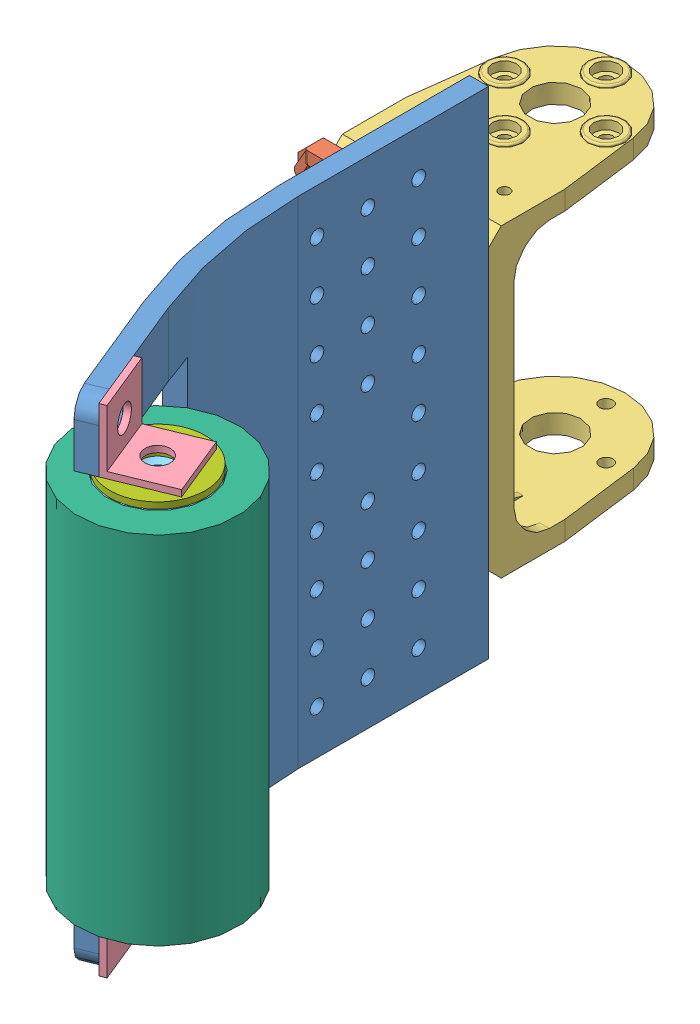
SolidWorks assembly essai_assemblage_pince_3_droite, configuration Default. Lengths in mm.
Overall size (56.85 78 117.91).
10 component instances, 7 part files, 23 mates.
Components (placement in the parent):
- essai_pince_6-1: essai_pince_6 [Default] at (-8.4781 -11.6289 -22.4125) size (15.55 78 75)
- F9ORG-1: F9ORG [Défaut] at (-8.4781 11.3711 -52.4125) x (1 0 0) z (0 0 -1) size (24 24 30)
- F2-1: F2 [Défaut] at (-20.9781 19.3711 -78.4125) x (0 1 0) z (0 0 1) size (48.81 25 37)
- corniere_10x10-3: corniere_10x10 [Default] at (12.5438 56.3711 8.412) x (-0.925648 0 0.378386) z (-0.378386 0 -0.925648) size (10 10 10)
- corniere_10x10-2: corniere_10x10 [Default] at (16.3277 -1.6289 17.6684) x (-0.925648 0 0.378386) z (0.378386 0 0.925648) size (10 10 10)
- F9ORG-2: F9ORG [Défaut] at (-8.4781 35.3711 -52.4125) x (1 0 0) z (0 0 -1) size (24 24 30)
- Rouleau_Laiton_D15_H56-1: Rouleau_Laiton_D15_H56 [Défaut] at (9.8075 -0.6289 14.9321) size (15 56 15)
- Rouleau_D25_H56-1: Rouleau_D25_H56 [Default] at (9.8075 -0.6289 14.9321) x (0.08937 0 0.995998) z (-0.995998 0 0.08937) size (25 56 25)
- Rondelle_M5_Large-1: Rondelle_M5_Large [Défaut] at (9.8075 55.3711 14.9321) x (-0.555891 0 0.831255) z (-0.831255 0 -0.555891) size (15 1 15)
- Rondelle_M5_Large-2: Rondelle_M5_Large [Défaut] at (9.8075 -1.6289 14.9321) x (-0.793326 0 -0.608798) z (0.608798 0 -0.793326) size (15 1 15)
Mates (geometry in assembly coordinates):
- Coïncidente3: coincident anti-aligned: plane of ? through (0 0 0) normal (0 0 1); plane of ? through (-33.4781 -6.3008 -51.8597) normal (0 0.062502 0.998045)
- Coïncidente4: coincident aligned: plane of ? through (-8.4781 21.6445 -53.6098) normal (1 0 0); plane of ? through (-8.4781 -6.3008 -51.8597) normal (1 0 0)
- Coïncidente5: coincident anti-aligned: plane of corniere_10x10-3 through (3.2873 57.3711 12.1958) normal (-0.925648 0 0.378386); plane of essai_pince_6-1 through (-0.4965 66.3711 2.9393) normal (0.925648 0 -0.378386)
- Coïncidente7: coincident anti-aligned: plane of essai_pince_6-1 through (-0.4965 66.3711 2.9393) normal (0.925648 0 -0.378386); plane of corniere_10x10-2 through (7.0712 -2.6289 21.4523) normal (-0.925648 0 0.378386)
- Coaxiale9: concentric anti-aligned: cylinder of ?; cylinder of ?
- Coïncidente15: coincident anti-aligned: plane of essai_pince_6-1 through (-8.4781 66.3711 -22.4125) normal (-1 0 0); plane of ? through (-8.4781 21.6445 -53.6098) normal (1 0 0)
- Coïncidente16: coincident anti-aligned: plane of ? through (0 0 0) normal (0 0 1); plane of ? through (-33.4781 45.5976 -55.1098) normal (0 -0.062502 -0.998045)
- Coïncidente17: coincident anti-aligned: plane of essai_pince_6-1 through (-8.4781 66.3711 -22.4125) normal (-1 0 0); plane of ? through (-8.4781 45.5976 -55.1098) normal (1 0 0)
- Coaxiale12: concentric anti-aligned: cylinder of ?; cylinder of ?
- Coaxiale13: concentric aligned: cylinder of essai_pince_6-1; cylinder of corniere_10x10-3
- Parallèle1: parallel aligned: plane of essai_pince_6-1 through (32.9437 56.3711 10.8761) normal (0 -1 0); plane of corniere_10x10-3 through (16.3277 56.3711 17.6684) normal (0 -1 0)
- Coaxiale14: concentric aligned: cylinder of Rouleau_Laiton_D15_H56-1; cylinder of Rouleau_D25_H56-1
- Coïncidente19: coincident aligned: plane of Rouleau_Laiton_D15_H56-1 through (9.8075 55.3711 14.9321) normal (0 1 0); plane of Rouleau_D25_H56-1 through (9.8075 55.3711 14.9321) normal (0 1 0)
- Coaxiale15: concentric aligned: cylinder of essai_pince_6-1; cylinder of corniere_10x10-2
- Coïncidente20: coincident aligned: plane of essai_pince_6-1 through (32.9437 -1.6289 10.8761) normal (0 1 0); plane of corniere_10x10-2 through (12.5438 -1.6289 8.412) normal (0 1 0)
- Coaxiale16: concentric aligned: cylinder of corniere_10x10-3; cylinder of Rouleau_Laiton_D15_H56-1
- Coaxiale17: concentric aligned: cylinder of Rouleau_Laiton_D15_H56-1; cylinder of Rondelle_M5_Large-2
- Coaxiale18: concentric aligned: cylinder of Rouleau_Laiton_D15_H56-1; cylinder of Rondelle_M5_Large-1
- Coïncidente21: coincident aligned: plane of Rouleau_Laiton_D15_H56-1 through (9.8075 55.3711 14.9321) normal (0 1 0); circle of Rondelle_M5_Large-1
- Coïncidente22: coincident anti-aligned: plane of Rouleau_Laiton_D15_H56-1 through (9.8075 -0.6289 14.9321) normal (0 -1 0); plane of Rondelle_M5_Large-2 through (9.8075 -0.6289 14.9321) normal (0 1 0)
- Coïncidente23: coincident anti-aligned: plane of corniere_10x10-2 through (12.5438 -1.6289 8.412) normal (0 1 0); plane of Rondelle_M5_Large-2 through (9.8075 -1.6289 14.9321) normal (0 -1 0)
- Coaxiale19: concentric aligned: cylinder of essai_pince_6-1; cylinder of ?
- Coaxiale20: concentric aligned: cylinder of essai_pince_6-1; cylinder of ?
